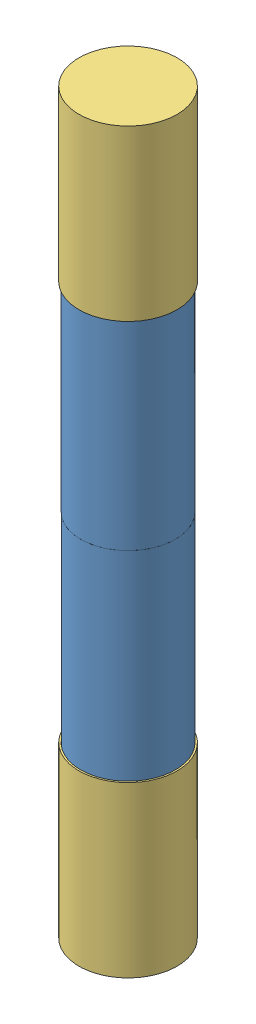
SolidWorks assembly iGem_assembly_V2, configuration Default. Lengths in mm.
Overall size (40.53 218 40.53).
6 component instances, 3 part files, 9 mates.
Components (placement in the parent):
- igem_core_half-1: igem_core_half [По умолчанию] at origin size (28 86 28)
- igem_core_half-2: igem_core_half [По умолчанию] at (17.3571 0 13.5915) x (-0.239796 0 -0.970823) z (-0.970823 0 0.239796) size (28 86 28)
- igem_spray-1: igem_spray [По умолчанию] at (14 72 0) size (22 107 22)
- igem_spray-2: igem_spray [По умолчанию] at (14 -72 0) x (-0.453658 0 0.891176) z (0.891176 0 0.453658) size (22 107 22)
- igem_cap-1: igem_cap [По умолчанию] at (14 -109 0) size (29 50 29)
- igem_cap-3: igem_cap [По умолчанию] at (14 109 0) x (0.80674 0 0.590906) z (0.590906 0 -0.80674) size (29 50 29)
Mates (geometry in assembly coordinates):
- Совпадение1: coincident anti-aligned: circle of igem_core_v2.2-1; circle of igem_core_v2.2-2
- Совпадение2: coincident anti-aligned: plane of igem_core_v2.2-1 through (5.5367 86 0) normal (0 1 0); plane of igem_spray-1 through (14 86 0) normal (0 -1 0)
- Концентричный1: concentric anti-aligned: circle of igem_core_v2.2-1; circle of igem_spray-1
- Концентричный2: concentric anti-aligned: circle of igem_core_v2.2-2; circle of igem_spray-2
- Совпадение3: coincident anti-aligned: plane of igem_core_v2.2-2 through (16.0295 -86 8.2163) normal (0 -1 0); plane of igem_spray-2 through (14 -86 0) normal (0 1 0)
- Совпадение4: coincident anti-aligned: plane of igem_spray-2 through (14 -108 0) normal (0 -1 0); circle of igem_cup_on_xyi-1
- Концентричный3: concentric aligned: circle of igem_core_v2.2-2; circle of igem_cup_on_xyi-1
- Концентричный4: concentric aligned: circle of igem_core_v2.2-1; circle of igem_cup_on_xyi-3
- Совпадение5: coincident anti-aligned: plane of igem_spray-1 through (14 108 0) normal (0 1 0); circle of igem_cup_on_xyi-3
